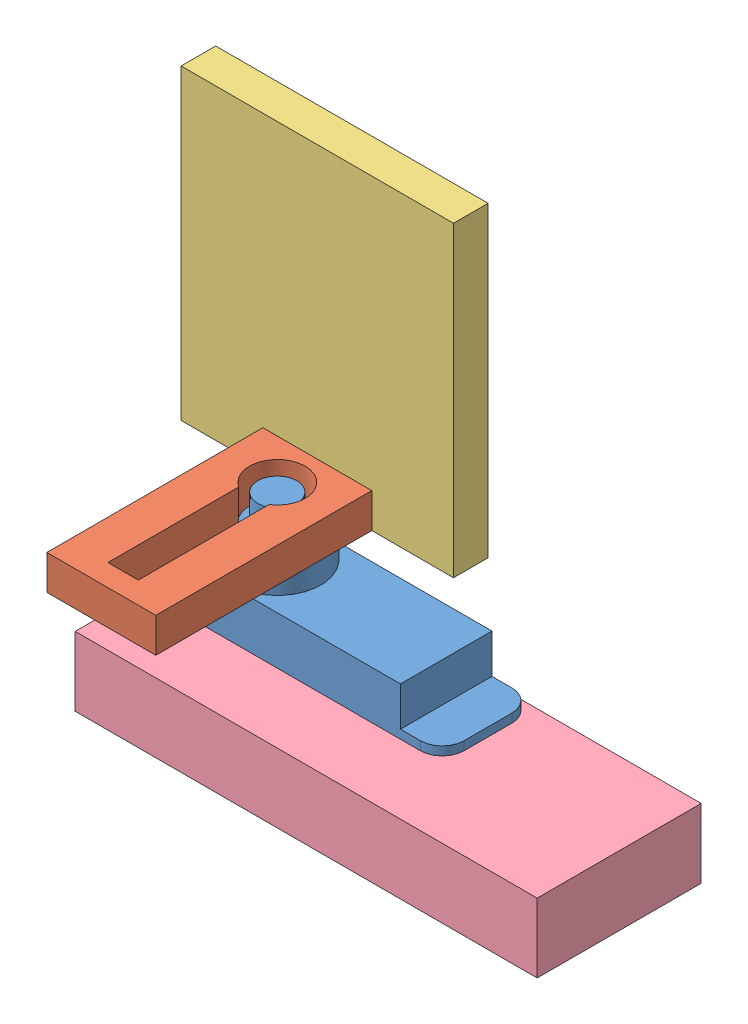
SolidWorks assembly Y-Servo and Mounts, configuration Default. Lengths in mm.
Overall size (53.9 47.47 23).
4 component instances, 4 part files, 6 mates.
Components (placement in the parent):
- Servo PowerHD DSP33-1: Servo PowerHD DSP33 [Default] at (10.3442 32.3124 38.838) size (27.17 21.7 8.4)
- Servo Cap Mount-1: Servo Cap Mount [Default] at (9.3442 51.6124 50.7904) size (10 3.17 23)
- Mirror Mount-1: Mirror Mount [Default] at (1.8442 79.7874 30.9654) x (1 0 0) z (0 1 0) size (25 3.17 28.17)
- Y-Servo Mount-1: Y-Servo Mount [Default] at (10.3442 37.8624 38.838) size (49.4 6.35 15.05)
Mates (geometry in assembly coordinates):
- Concentric1: concentric aligned: circle of Servo Cap Mount-1; circle of Servo PowerHD DSP33-1
- Distance1: distance = 1 mm anti-aligned: plane of Servo PowerHD DSP33-1 through (14.3442 50.6124 34.638) normal (0 1 0); plane of Servo Cap Mount-1 through (9.3442 51.6124 50.7904) normal (0 -1 0)
- Coincident10: coincident: point of Servo Cap Mount-1; point of Mirror Mount-1
- Coincident11: coincident: point of Servo Cap Mount-1; point of Mirror Mount-1
- Coincident12: coincident: line of Servo Cap Mount-1 through (17.3442 51.6124 30.9654) axis (-1 0 0); plane of Mirror Mount-1 through (1.8442 79.7874 30.9654) normal (0 0 1)
- Coincident13: coincident: point of Servo PowerHD DSP33-1; point of Y-Servo Mount-1
